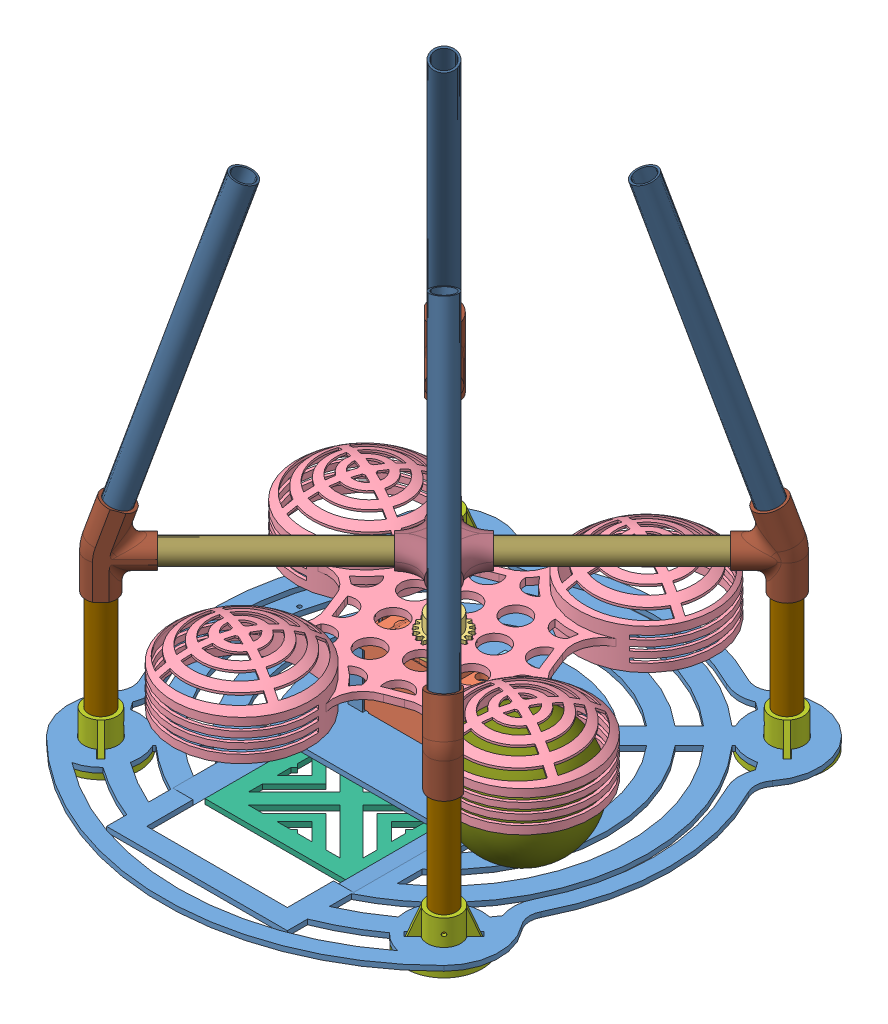
SolidWorks assembly Top Bırakma Tepsisi, configuration Varsayılan. Lengths in mm.
Overall size (291.11 263.36 291.11).
31 component instances, 16 part files, 45 mates.
Components (placement in the parent):
- Alt Tabla-1: Alt Tabla [Varsayılan] at (-35.3961 -10.7473 250) size (225 36.5 252.5)
- TP MG996R-1: TP MG996R [Default] at (-45.4902 -8.2473 250) size (58.18 41.75 20)
- pinion redesigned-1: pinion redesigned [Varsayılan] at (-35.3961 33.4027 250) x (0.17199 0 0.985099) z (-0.985099 0 0.17199) size (22.91 15 22.91)
- sepet-1: sepet [Varsayılan] at (-35.3961 33.4027 250) x (0.915628 0 0.402026) z (-0.402026 0 0.915628) size (220.93 32.76 220.93)
- TP SG90-1: TP SG90 [Varsayılan] at (-21.6461 15.8527 228) x (0 0 -1) z (-1 0 0) size (12.64 29.82 33.01)
- Alt Kapak-1: Alt Kapak [Varsayılan] at (-70.3961 -13.2473 334.0208) size (73 2.5 120)
- Bağlantı Parçası-1: Bağlantı Parçası [Varsayılan] at (-120.8146 -13.7473 164.5815) x (-0.707107 0 0.707107) z (-0.707107 0 -0.707107) size (38.11 18 38.11)
- Bağlantı Parçası-2: Bağlantı Parçası [Varsayılan] at (50.0224 -13.7473 335.4185) x (0.707107 0 -0.707107) z (0.707107 0 0.707107) size (38.11 18 38.11)
- Bağlantı Parçası-3: Bağlantı Parçası [Varsayılan] at (50.0224 -13.7473 164.5815) x (-0.707107 0 -0.707107) z (0.707107 0 -0.707107) size (38.11 18 38.11)
- Bağlantı Parçası-4: Bağlantı Parçası [Varsayılan] at (-120.8146 -13.7473 335.4185) x (-0.707107 0 -0.707107) z (0.707107 0 -0.707107) size (38.11 18 38.11)
- Alt Kapak Bağlantısı-1: Alt Kapak Bağlantısı [Varsayılan] at (-26.8961 -13.2473 228) x (-0.999996 0 -0.002779) z (0.002779 0 -0.999996) size (5.8 3 10.81)
- karbonfiber boru 12x75-1: karbonfiber boru 12x75 [Varsayılan] at (-120.8146 -10.7473 335.4185) x (-0.707107 0 0.707107) z (0 1 0) size (12 12 75)
- karbonfiber boru 12x400-5: karbonfiber boru 12x400 [Varsayılan] at (-85.3052 233.5234 299.9091) x (0.968425 -0.234673 -0.084156) z (-0.212631 -0.953717 0.212631) size (12 12 157)
- Dirsek-1: Dirsek [Varsayılan] at (-120.8146 54.2527 335.4185) x (-0.707107 0 -0.707107) z (0.707107 0 -0.707107) size (15.76 41.33 27.5)
- karbonfiber boru 11x100-1: karbonfiber boru 11x100 [Varsayılan] at (-40.9115 71.5592 255.5154) x (-0.566236 -0.59896 -0.566236) z (-0.707107 0 0.707107) size (11 11 103)
- baglantı-1: baglantı [Varsayılan] at (-35.3961 64.0592 250) x (0.707107 0 0.707107) z (-0.707107 0 0.707107) size (35 15.09 35)
- Dirsek-2: Dirsek [Varsayılan] at (-120.8146 54.2527 164.5815) x (0.707107 0 -0.707107) z (0.707107 0 0.707107) size (15.76 41.33 27.5)
- Dirsek-3: Dirsek [Varsayılan] at (50.0224 54.2527 164.5815) x (0.707107 0 0.707107) z (-0.707107 0 0.707107) size (15.76 41.33 27.5)
- Dirsek-4: Dirsek [Varsayılan] at (50.0224 54.2527 335.4185) x (-0.707107 0 0.707107) z (-0.707107 0 -0.707107) size (15.76 41.33 27.5)
- karbonfiber boru 12x75-2: karbonfiber boru 12x75 [Varsayılan] at (-120.8146 -10.7473 164.5815) x (-0.707107 0 -0.707107) z (0 1 0) size (12 12 75)
- karbonfiber boru 12x75-3: karbonfiber boru 12x75 [Varsayılan] at (50.0224 -10.7473 164.5815) x (0.707107 0 -0.707107) z (0 1 0) size (12 12 75)
- karbonfiber boru 12x75-4: karbonfiber boru 12x75 [Varsayılan] at (50.0224 -10.7473 335.4185) x (0.707107 0 0.707107) z (0 1 0) size (12 12 75)
- karbonfiber boru 11x100-2: karbonfiber boru 11x100 [Varsayılan] at (-40.9115 71.5592 244.4846) x (0.566236 -0.59896 -0.566236) z (-0.707107 0 -0.707107) size (11 11 103)
- karbonfiber boru 11x100-3: karbonfiber boru 11x100 [Varsayılan] at (-29.8807 71.5592 244.4846) x (0.566236 -0.59896 0.566236) z (0.707107 0 -0.707107) size (11 11 103)
- karbonfiber boru 11x100-4: karbonfiber boru 11x100 [Varsayılan] at (-29.8807 71.5592 255.5154) x (-0.566236 -0.59896 0.566236) z (0.707107 0 0.707107) size (11 11 103)
- karbonfiber boru 12x400-6: karbonfiber boru 12x400 [Varsayılan] at (-85.3052 233.5234 200.0909) x (0.084156 -0.234673 0.968425) z (-0.212631 -0.953717 -0.212631) size (12 12 157)
- karbonfiber boru 12x400-7: karbonfiber boru 12x400 [Varsayılan] at (14.513 233.5234 200.0909) x (-0.968425 -0.234673 0.084156) z (0.212631 -0.953717 -0.212631) size (12 12 157)
- karbonfiber boru 12x400-8: karbonfiber boru 12x400 [Varsayılan] at (14.513 233.5234 299.9091) x (-0.084156 -0.234673 -0.968425) z (0.212631 -0.953717 0.212631) size (12 12 157)
- Dengeleyici-1: Dengeleyici [Varsayılan] at (-35.3961 77.0592 250) x (-0.316407 0 -0.948624) z (-0.948624 0 0.316407) size (9.6 10 9.6)
- Yivli mil-1: Yivli mil [Varsayılan] at (-35.3961 38.4592 250) x (0.806296 0 0.591513) z (-0.591513 0 0.806296) size (5.06 35.91 5.78)
- Top-1: Top [Varsayılan] at (34.6181 21.7527 280.7412) x (0.839785 -0.275982 -0.467542) z (0.169213 -0.68522 0.708407) size (60 60 60)
Mates (geometry in assembly coordinates):
- Çakışık1: coincident: plane of assembly; plane of Alt Tabla-1 through (-35.3961 -8.2473 250) normal (0 1 0); plane of TP MG996R-1 through (-45.4902 -8.2473 250) normal (0 -1 0)
- Eş Merkezli1: concentric: cylinder of assembly; cylinder of Alt Tabla-1 through (-35.3961 -17.7473 250) axis (0 1 0) radius 112.5; cylinder of TP MG996R-1 through (-35.3961 17.2527 250) axis (0 1 0) radius 5
- Paralel1: parallel aligned: plane of Alt Tabla-1 through (-70.3961 -8.2473 290) normal (0 0 1); plane of TP MG996R-1 through (-65.4902 26.7527 260) normal (0 0 1)
- Eş Merkezli2: concentric aligned: cylinder of TP MG996R-1 through (-35.3961 17.2527 250) axis (0 1 0) radius 5; cylinder of pinion redesigned-1 through (-35.3961 30.4027 250) axis (0 1 0) radius 11.4571
- Eş Merkezli3: concentric aligned: cylinder of pinion redesigned-1 through (-35.3961 74.1111 250) axis (0 -1 0) radius 7.6751; cylinder of sepet-1 through (-35.3961 36.9027 250) axis (0 -1 0) radius 43.9658
- Çakışık4: coincident anti-aligned: plane of pinion redesigned-1 through (-35.3961 33.4027 250) normal (0 1 0); plane of sepet-1 through (-35.3961 33.4027 250) normal (0 -1 0)
- Paralel2: parallel aligned: plane of pinion redesigned-1 through (-38.7255 38.4027 252.8633) normal (-0.758183 0 0.652042); plane of sepet-1 through (-31.8392 23.4027 246.9411) normal (-0.758183 0 0.652042)
- Eş Merkezli4: concentric aligned: cylinder of Alt Tabla-1 through (-26.8961 -8.2473 228) axis (0 -1 0) radius 6.65; cylinder of TP SG90-1 through (-26.8961 -6.6473 228) axis (0 -1 0) radius 6.25
- Çakışık8: coincident aligned: plane of Alt Tabla-1 through (-35.3961 -10.7473 250) normal (0 -1 0); plane of TP SG90-1 through (-26.2086 -10.7473 228) normal (0 -1 0)
- Çakışık9: coincident anti-aligned: plane of Alt Tabla-1 through (-35.3961 -10.7473 250) normal (0 -1 0); plane of Alt Kapak-1 through (-70.3961 -10.7473 334.0208) normal (0 1 0)
- Eş Merkezli8: concentric aligned: cylinder of Alt Tabla-1 through (-26.8961 -8.2473 228) axis (0 -1 0) radius 6.65; cylinder of Alt Kapak-1 through (-26.8961 -10.7473 228) axis (0 -1 0) radius 3
- Açıyı Sınırla3: limit planar angle = 0 rad anti-aligned: plane of Alt Tabla-1 through (2.6039 -14.7473 250) normal (-1 0 0); plane of Alt Kapak-1 through (2.6039 -10.7473 334.0208) normal (1 0 0)
- Eş Merkezli9: concentric: cylinder of assembly; cylinder of Alt Tabla-1 through (-120.8146 -17.7473 164.5815) axis (0 1 0) radius 8.3; cylinder of Bağlantı Parçası-1 through (-120.8146 42.0215 164.5815) axis (0 -1 0) radius 6.05
- Çakışık10: coincident anti-aligned: plane of Alt Tabla-1 through (-35.3961 -10.7473 250) normal (0 -1 0); plane of Bağlantı Parçası-1 through (-120.8146 -10.7473 164.5815) normal (0 1 0)
- Eş Merkezli10: concentric: cylinder of assembly; cylinder of Alt Tabla-1 through (50.0224 -17.7473 335.4185) axis (0 1 0) radius 8.3; cylinder of Bağlantı Parçası-2 through (50.0224 42.0215 335.4185) axis (0 -1 0) radius 6.05
- Paralel3: parallel anti-aligned: plane of Alt Tabla-1 through (-125.5263 -17.7473 171.4145) normal (-0.707107 0 -0.707107); plane of Bağlantı Parçası-1 through (-119.9307 10.7527 165.4654) normal (0.707107 0 0.707107)
- Eş Merkezli11: concentric anti-aligned: cylinder of Alt Tabla-1 through (50.0224 -17.7473 164.5815) axis (0 1 0) radius 8.3; cylinder of Bağlantı Parçası-3 through (50.0224 42.0215 164.5815) axis (0 -1 0) radius 6.05
- Paralel4: parallel aligned: plane of Alt Tabla-1 through (45.3107 -17.7473 157.7485) normal (-0.707107 0 0.707107); plane of Bağlantı Parçası-3 through (49.1385 10.7527 165.4654) normal (-0.707107 0 0.707107)
- Çakışık13: coincident anti-aligned: plane of Alt Tabla-1 through (-35.3961 -10.7473 250) normal (0 -1 0); plane of Bağlantı Parçası-3 through (50.0224 -10.7473 164.5815) normal (0 1 0)
- Çakışık14: coincident anti-aligned: plane of Alt Tabla-1 through (-35.3961 -10.7473 250) normal (0 -1 0); plane of Bağlantı Parçası-2 through (50.0224 -10.7473 335.4185) normal (0 1 0)
- Paralel5: parallel aligned: plane of Alt Tabla-1 through (54.7341 -17.7473 328.5855) normal (0.707107 0 0.707107); plane of Bağlantı Parçası-2 through (50.9063 10.7527 336.3024) normal (0.707107 0 0.707107)
- Eş Merkezli12: concentric anti-aligned: cylinder of Alt Tabla-1 through (-120.8146 -17.7473 335.4185) axis (0 1 0) radius 8.3; cylinder of Bağlantı Parçası-4 through (-120.8146 42.0215 335.4185) axis (0 -1 0) radius 6.05
- Çakışık16: coincident anti-aligned: plane of Alt Tabla-1 through (-35.3961 -10.7473 250) normal (0 -1 0); plane of Bağlantı Parçası-4 through (-120.8146 -10.7473 335.4185) normal (0 1 0)
- Paralel6: parallel aligned: plane of Alt Tabla-1 through (-116.1029 -17.7473 342.2515) normal (0.707107 0 -0.707107); plane of Bağlantı Parçası-4 through (-119.9307 10.7527 334.5346) normal (0.707107 0 -0.707107)
- Çakışık22: coincident aligned: plane of Alt Kapak-1 through (-70.3961 -13.2473 334.0208) normal (0 -1 0); plane of Alt Kapak Bağlantısı-1 through (-26.8961 -13.2473 228) normal (0 -1 0)
- Eş Merkezli25: concentric aligned: cylinder of Alt Kapak-1 through (-26.8961 -10.7473 228) axis (0 -1 0) radius 3; cylinder of Alt Kapak Bağlantısı-1 through (-26.8961 -10.2473 228) axis (0 -1 0) radius 2.9
- Çakışık26: coincident anti-aligned: plane of TP MG996R-1 through (-45.4902 33.5027 250) normal (0 1 0); plane of pinion redesigned-1 through (-35.3961 33.5027 250) normal (0 -1 0)
- Eş Merkezli33: concentric aligned: cylinder of Bağlantı Parçası-4 through (-120.8146 42.0215 335.4185) axis (0 -1 0) radius 6.05; cylinder of karbonfiber boru 12x75-1 through (-120.8146 64.2527 335.4185) axis (0 -1 0) radius 6
- Çakışık27: coincident anti-aligned: plane of Bağlantı Parçası-4 through (-120.8146 -10.7473 335.4185) normal (0 1 0); plane of karbonfiber boru 12x75-1 through (-120.8146 -10.7473 335.4185) normal (0 -1 0)
- Eş Merkezli34: concentric anti-aligned: cylinder of Bağlantı Parçası-4 through (-134.2882 -2.7473 348.8921) axis (0.707107 0 -0.707107) radius 1; cylinder of karbonfiber boru 12x75-1 through (-116.572 -2.7473 331.1759) axis (-0.707107 0 0.707107) radius 1
- Coincident1: coincident anti-aligned: plane of karbonfiber boru 12x75-1 through (-120.8146 64.2527 335.4185) normal (0 1 0); plane of Dirsek-1 through (-120.8146 64.2527 335.4185) normal (0 -1 0)
- Concentric1: concentric aligned: cylinder of karbonfiber boru 12x75-1 through (-120.8146 64.2527 335.4185) axis (0 -1 0) radius 6; cylinder of Dirsek-1 through (-120.8146 64.2527 335.4185) axis (0 -1 0) radius 6.05
- Coincident2: coincident anti-aligned: plane of karbonfiber boru 12x400-5 through (-118.6883 83.7899 333.2922) normal (-0.212631 -0.953717 0.212631); plane of Dirsek-1 through (-118.6883 83.7899 333.2922) normal (0.212631 0.953717 -0.212631)
- Concentric2: concentric aligned: cylinder of karbonfiber boru 12x400-5 through (-118.6883 83.7899 333.2922) axis (0.212631 0.953717 -0.212631) radius 6; cylinder of Dirsek-1 through (-118.6883 83.7899 333.2922) axis (0.212631 0.953717 -0.212631) radius 6.05
- Concentric3: concentric aligned: cylinder of Dirsek-1 through (-113.7435 71.5592 328.3474) axis (0.707107 0 -0.707107) radius 5.6; cylinder of karbonfiber boru 11x100-1 through (-113.7435 71.5592 328.3474) axis (0.707107 0 -0.707107) radius 5.5
- Coincident3: coincident anti-aligned: plane of Dirsek-1 through (-113.7435 71.5592 328.3474) normal (0.707107 0 -0.707107); plane of karbonfiber boru 11x100-1 through (-113.7435 71.5592 328.3474) normal (-0.707107 0 0.707107)
- Eş Merkezli35: concentric aligned: cylinder of pinion redesigned-1 through (-35.3961 74.1111 250) axis (0 -1 0) radius 2.5; cylinder of baglantı-1 through (-35.3961 79.0592 250) axis (0 -1 0) radius 5
- Eş Merkezli36: concentric aligned: cylinder of Dirsek-1 through (-106.6725 71.5592 321.2764) axis (-0.707107 0 0.707107) radius 7; cylinder of baglantı-1 through (-40.6994 71.5592 255.3033) axis (-0.707107 0 0.707107) radius 5.6
- Eş Merkezli37: concentric anti-aligned: cylinder of baglantı-1 through (-35.3961 79.0592 250) axis (0 -1 0) radius 5; cylinder of Dengeleyici-1 through (-35.3961 67.0592 250) axis (0 1 0) radius 4.8
- Çakışık28: coincident anti-aligned: plane of baglantı-1 through (-35.3961 67.0592 250) normal (0 1 0); plane of Dengeleyici-1 through (-35.3961 67.0592 250) normal (0 -1 0)
- Eş Merkezli38: concentric anti-aligned: cylinder of Dengeleyici-1 through (-35.3961 74.0592 250) axis (0 -1 0) radius 2.5; cone of Yivli mil-1 through (-35.3961 74.0592 250) axis (0 1 0)
- Çakışık29: coincident anti-aligned: plane of Dengeleyici-1 through (-35.3961 74.0592 250) normal (0 -1 0); plane of Yivli mil-1 through (-35.3961 74.0592 250) normal (0 1 0)
- Eş Merkezli39: concentric aligned: cylinder of pinion redesigned-1 through (-35.3961 74.1111 250) axis (0 -1 0) radius 2.5; cone of Yivli mil-1 through (-35.3961 38.9592 250) axis (0 -1 0)
- Teğet2: tangent anti-aligned: sphere of Top-1; plane of Alt Tabla-1 through (-35.3961 -8.2473 250) normal (0 1 0)
- Eş Merkezli41: concentric: cylinder of sepet-1 through (34.6181 43.4027 280.7412) axis (0 -1 0) radius 32.5; sphere of Top-1
